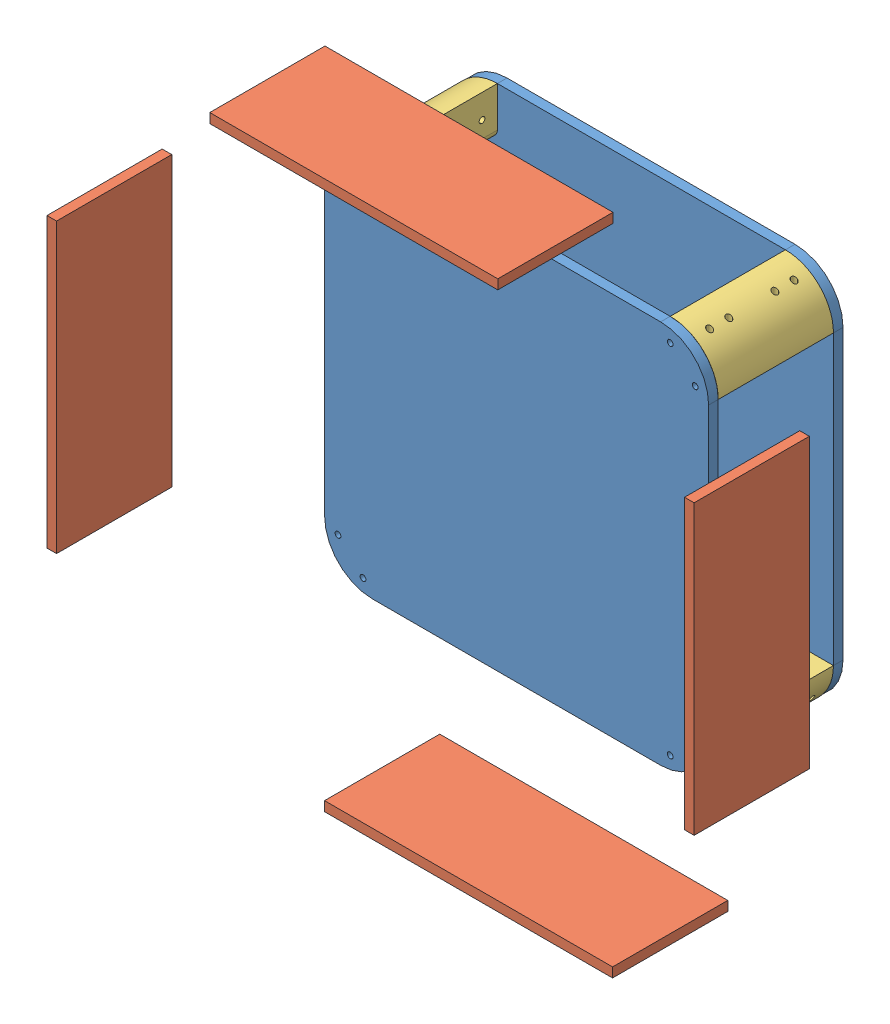
SolidWorks assembly Braço, configuration Valor predeterminado. Lengths in mm.
Overall size (318.97 377.4 169.43).
10 component instances, 3 part files, 15 mates.
Components (placement in the parent):
- Cima Baixo base-1: Cima Baixo base [Valor predeterminado] at (-21.8836 327.4467 197.5) size (200 200 5)
- Parede base-1: Parede base [Valor predeterminado] at (46.7742 -13.8063 211.039) x (0 -1 0) z (0 0 1) size (150 5 60)
- Parede base-2: Parede base [Valor predeterminado] at (-7.2535 403.8922 241.9266) size (150 5 60)
- Parede base-3: Parede base [Valor predeterminado] at (-106.927 -9.63 192.9819) x (0 1 0) z (0 0 1) size (150 5 60)
- Parede base-4: Parede base [Valor predeterminado] at (-39.4301 31.4925 149.9788) size (150 5 60)
- Angulo base-1: Angulo base [Valor predeterminado] at (-344.8618 -12.2461 137.5) x (0 1 0) z (0 0 1) size (25 25 60)
- Angulo base-2: Angulo base [Valor predeterminado] at (317.8092 4.4685 137.5) x (0 -1 0) z (0 0 1) size (25 25 60)
- Angulo base-3: Angulo base [Valor predeterminado] at (-21.8836 327.4467 137.5) size (25 25 60)
- Angulo base-4: Angulo base [Valor predeterminado] at (-5.1691 -335.2243 137.5) x (-1 0 0) z (0 0 1) size (25 25 60)
- Cima Baixo base-2: Cima Baixo base [Valor predeterminado] at (-21.8836 327.4467 132.5) size (200 200 5)
Mates (geometry in assembly coordinates):
- Concêntrico1: concentric anti-aligned: circle of Cima Baixo base-1; circle of Angulo base-4
- Concêntrico2: concentric anti-aligned: circle of Cima Baixo base-1; circle of Angulo base-4
- Concêntrico8: concentric: circle of Cima Baixo base-1; circle of Angulo base-1
- Concêntrico9: concentric: circle of Cima Baixo base-1; circle of Angulo base-1
- Concêntrico3: concentric anti-aligned: circle of Cima Baixo base-1; circle of Angulo base-2
- Concêntrico5: concentric anti-aligned: circle of Cima Baixo base-1; circle of Angulo base-2
- Concêntrico6: concentric anti-aligned: circle of Cima Baixo base-1; circle of Angulo base-3
- Concêntrico7: concentric anti-aligned: circle of Cima Baixo base-1; circle of Angulo base-3
- Coincidente40: coincident anti-aligned: plane of Cima Baixo base-1 through (-88.5263 71.1112 197.5) normal (0 0 -1); plane of Angulo base-1 through (-88.5263 71.1112 197.5) normal (0 0 1)
- Coincidente41: coincident anti-aligned: plane of Cima Baixo base-1 through (-88.5263 71.1112 197.5) normal (0 0 -1); plane of Angulo base-3 through (61.4737 71.1112 197.5) normal (0 0 1)
- Coincidente42: coincident anti-aligned: plane of Cima Baixo base-1 through (-88.5263 71.1112 197.5) normal (0 0 -1); plane of Angulo base-2 through (61.4737 -78.8888 197.5) normal (0 0 1)
- Coincidente43: coincident anti-aligned: plane of Cima Baixo base-1 through (-88.5263 71.1112 197.5) normal (0 0 -1); plane of Angulo base-4 through (-88.5263 -78.8888 197.5) normal (0 0 1)
- Concêntrico10: concentric anti-aligned: circle of Angulo base-3; circle of Cima Baixo base-2
- Concêntrico11: concentric anti-aligned: circle of Angulo base-4; circle of Cima Baixo base-2
- Coincidente47: coincident anti-aligned: plane of Angulo base-2 through (61.4737 -78.8888 137.5) normal (0 0 -1); plane of Cima Baixo base-2 through (-88.5263 71.1112 137.5) normal (0 0 1)
